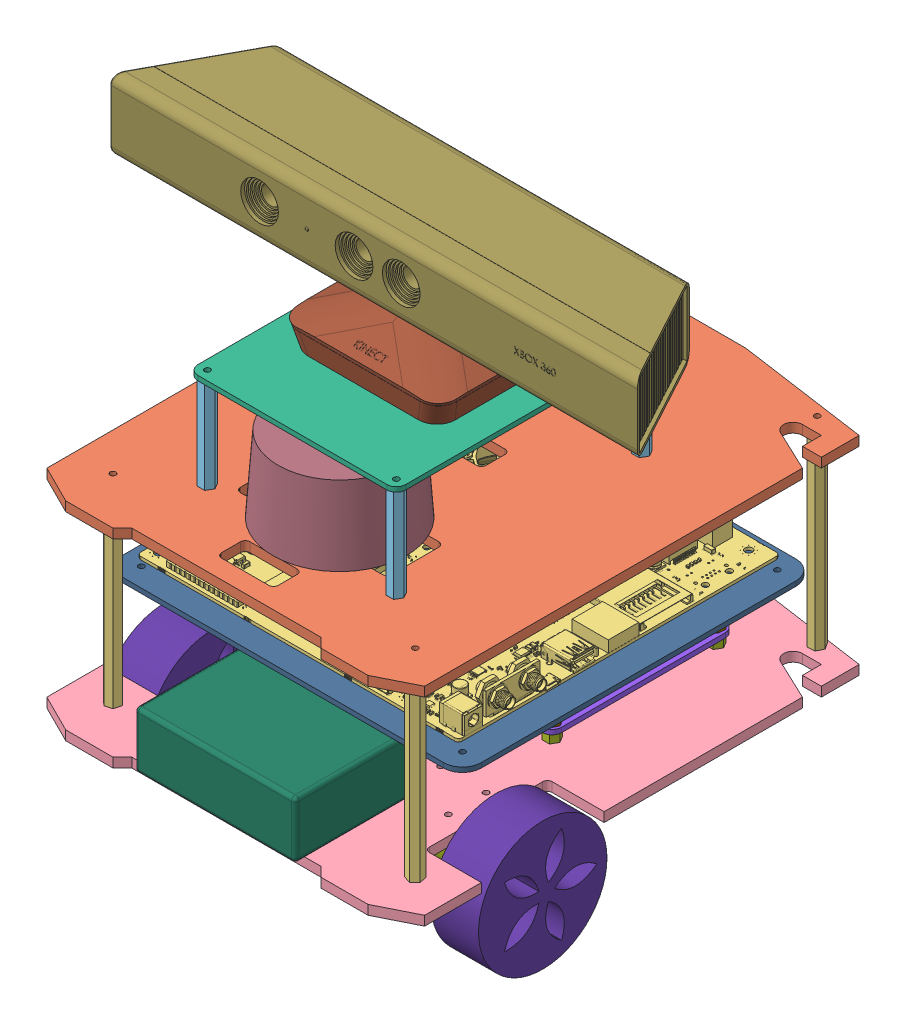
SolidWorks assembly 装配体1, configuration 默认. Lengths in mm.
Overall size (279.32 286 251).
37 component instances, 21 part files, 74 mates.
Components (placement in the parent):
- 电机支架-1: 电机支架 [默认] at (-13.0995 14.6371 109.2273) x (0 0 1) z (1 0 0) size (30 32 40)
- 上顶板-1: 上顶板 [默认] at (-83.0995 119.6371 56.7273) size (200 5 250)
- 铜柱-1: 铜柱 [默认] at (-163.0995 19.6371 156.7273) x (0.246222 0 -0.969214) z (0.969214 0 0.246222) size (8 100 6.94)
- 下地板-1: 下地板 [默认] at (-83.0995 14.6371 56.7273) size (200 5 250)
- 铜柱-2: 铜柱 [默认] at (-3.0995 19.6371 156.7273) x (0.949758 0 0.312985) z (-0.312985 0 0.949758) size (8 100 6.94)
- 铜柱-3: 铜柱 [默认] at (-163.0995 19.6371 -56.0791) size (8 100 6.94)
- 铜柱-4: 铜柱 [默认] at (-3.0995 19.6371 -56.0791) x (0.446339 0 -0.894864) z (0.894864 0 0.446339) size (8 100 6.94)
- 电机支架-2: 电机支架 [默认] at (-153.0995 14.6371 109.2273) x (0 0 -1) z (-1 0 0) size (30 32 40)
- 短铜柱-1: 短铜柱 [默认] at (-33.0995 124.6371 136.7273) size (8 50 6.94)
- 短铜柱-2: 短铜柱 [默认] at (-133.0995 124.6371 6.7273) size (8 50 6.94)
- 短铜柱-3: 短铜柱 [默认] at (-133.0995 124.6371 136.7273) size (8 50 6.94)
- 短铜柱-4: 短铜柱 [默认] at (-33.0995 124.6371 6.7273) size (8 50 6.94)
- 摄像头底板-1: 摄像头底板 [默认] at (0 -2.5 0) size (110 2.5 140)
- 超短铜柱-1: 超短铜柱 [默认] at (-30.5685 19.6371 56.7273) size (8 5.19 6.94)
- 超短铜柱-2: 超短铜柱 [默认] at (-30.5685 19.6371 -29.9177) size (8 5.19 6.94)
- 超短铜柱-3: 超短铜柱 [默认] at (-135.6304 19.6371 -29.9177) size (8 5.19 6.94)
- 超短铜柱-4: 超短铜柱 [默认] at (-135.6304 19.6371 56.7273) size (8 5.19 6.94)
- 下位机底板-1: 下位机底板 [默认] at origin size (115.06 2.5 96.65)
- tx2短铜柱-1: tx2短铜柱 [默认] at (-135.6304 27.1371 56.7273) x (0.774134 0 -0.633021) z (0.633021 0 0.774134) size (8 40 6.94)
- tx2短铜柱-2: tx2短铜柱 [默认] at (-30.5685 27.1371 56.7273) x (0.996933 0 -0.078265) z (0.078265 0 0.996933) size (8 40 6.94)
- tx2短铜柱-3: tx2短铜柱 [默认] at (-30.5685 27.1371 -29.9177) x (0.794955 0 0.606669) z (-0.606669 0 0.794955) size (8 40 6.94)
- tx2短铜柱-4: tx2短铜柱 [默认] at (-135.6304 27.1371 -29.9177) x (0.936829 0 0.349787) z (-0.349787 0 0.936829) size (8 40 6.94)
- tx2底板-1: tx2底板 [默认] at origin size (190 2.5 186.65)
- final kinect-1: final kinect [Default] at (-85.2291 193.8126 70.7637) size (279.32 72.5 71.02)
  - lower part-1: lower part [Default] at (2.1296 -16.1755 0.9636) size (86.05 27.21 71.02)
  - kinect upper part-1: kinect upper part [Default] at (2.268 17.8245 -1.5083) size (279.32 60 60)
- 雷达-1: 雷达 [默认] at (-83.0995 124.6371 116.7273) size (70.59 40 70.59)
- arduino MEGA2650-1: arduino MEGA2650 [默认] at (-37.5334 28.7371 -34.9177) x (0 0 -1) z (1 0 0) size (53.35 15.26 107.97)
- 电池-1: 电池 [默认] at (-83.0995 19.6371 152.7273) x (0 0 -1) z (1 0 0) size (60 30 85)
- 电机-1: 电机 [默认] at (-65.0995 -2.3629 109.2273) x (0 -1 0) z (0 0 1) size (25 70 25)
- 电机-2: 电机 [默认] at (-101.0995 -2.3629 109.2273) x (0 -1 0) z (0 0 -1) size (25 70 25)
- 轮子-1: 轮子 [默认] at (-183.0995 -2.3629 109.2273) x (0 -1 0) z (0 0 1) size (68 25 68)
- 轮子-2: 轮子 [默认] at (-8.0995 -2.3629 109.2273) x (0 -1 0) z (0 0 1) size (68 25 68)
- 板-1: 板 [默认] at (-83.0995 13.6371 -43.2727) size (40 1 40)
- 架-1: 架 [默认] at (-83.0995 13.6371 -43.2727) x (-1 0 0) z (0 0 1) size (16 36 30)
- 轮-1: 轮 [默认] at (-78.0995 -17.3629 -44.1872) x (0 1 0) z (0 0 1) size (35 10 35)
- tx2整体-1: tx2整体 [Default] at (-120.4205 78.1971 41.0823) x (1 0 0) z (0 1 0) size (186.12 170.18 41.03)
Mates (geometry in assembly coordinates):
- 同心1: concentric: cylinder of 铜柱-1 through (-163.0995 29.6371 156.7273) axis (0 -1 0) radius 1.5; cylinder of 下地板-1 through (-163.0995 9.6371 156.7273) axis (0 1 0) radius 1.5
- 重合1: coincident: plane of 铜柱-1 through (-163.0995 19.6371 156.7273) normal (0 -1 0); plane of 下地板-1 through (-83.0995 19.6371 56.7273) normal (0 1 0)
- 同心2: concentric: cylinder of 下地板-1 through (-3.0995 9.6371 156.7273) axis (0 1 0) radius 1.5; cylinder of 铜柱-2 through (-3.0995 29.6371 156.7273) axis (0 -1 0) radius 1.5
- 重合2: coincident: plane of 下地板-1 through (-83.0995 19.6371 56.7273) normal (0 1 0); plane of 铜柱-2 through (-3.0995 19.6371 156.7273) normal (0 -1 0)
- 重合3: coincident: plane of 下地板-1 through (-83.0995 19.6371 56.7273) normal (0 1 0); plane of 铜柱-3 through (-163.0995 19.6371 -56.0791) normal (0 -1 0)
- 同心3: concentric: cylinder of 下地板-1 through (-163.0995 9.6371 -56.0791) axis (0 1 0) radius 1.5; cylinder of 铜柱-3 through (-163.0995 29.6371 -56.0791) axis (0 -1 0) radius 1.5
- 同心4: concentric: cylinder of 下地板-1 through (-3.0995 9.6371 -56.0791) axis (0 1 0) radius 1.5; cylinder of 铜柱-4 through (-3.0995 29.6371 -56.0791) axis (0 -1 0) radius 1.5
- 重合4: coincident: plane of 下地板-1 through (-83.0995 19.6371 56.7273) normal (0 1 0); plane of 铜柱-4 through (-3.0995 19.6371 -56.0791) normal (0 -1 0)
- 重合5: coincident: plane of 上顶板-1 through (-83.0995 119.6371 56.7273) normal (0 -1 0); plane of 铜柱-1 through (-163.0995 119.6371 156.7273) normal (0 1 0)
- 同心5: concentric: cylinder of 上顶板-1 through (-163.0995 114.6371 156.7273) axis (0 1 0) radius 1.5; cylinder of 铜柱-1 through (-163.0995 109.6371 156.7273) axis (0 1 0) radius 1.5
- 同心6: concentric: cylinder of 上顶板-1 through (-3.0995 114.6371 156.7273) axis (0 1 0) radius 1.5; cylinder of 铜柱-2 through (-3.0995 109.6371 156.7273) axis (0 1 0) radius 1.5
- 重合6: coincident: plane of 电机支架-1 through (-50.5995 14.6371 96.7273) normal (0 1 0); plane of 下地板-1 through (-83.0995 14.6371 56.7273) normal (0 -1 0)
- 重合7: coincident: plane of 电机支架-1 through (-13.0995 12.6371 94.2273) normal (1 0 0); plane of 下地板-1 through (-13.0995 9.6371 139.2273) normal (1 0 0)
- 重合8: coincident: plane of 电机支架-1 through (-13.0995 14.6371 109.2273) normal (0 0 1); plane of 下地板-1 through (-83.0995 14.6371 109.2273) normal (0 0 1)
- 重合9: coincident: plane of 下地板-1 through (-83.0995 14.6371 56.7273) normal (0 -1 0); plane of 电机支架-2 through (-115.5995 14.6371 121.7273) normal (0 1 0)
- 同心7: concentric: cylinder of 下地板-1 through (-119.0995 24.6371 99.2273) axis (0 -1 0) radius 1.5; cylinder of 电机支架-2 through (-119.0995 2.6371 99.2273) axis (0 1 0) radius 1.5
- 同心8: concentric: cylinder of 下地板-1 through (-119.0995 24.6371 119.2273) axis (0 -1 0) radius 1.5; cylinder of 电机支架-2 through (-119.0995 2.6371 119.2273) axis (0 1 0) radius 1.5
- 同心9: concentric: cylinder of 上顶板-1 through (-133.0995 114.6371 136.7273) axis (0 1 0) radius 1.5; cylinder of 短铜柱-3 through (-133.0995 134.6371 136.7273) axis (0 -1 0) radius 1.5
- 同心10: concentric: cylinder of 上顶板-1 through (-33.0995 114.6371 136.7273) axis (0 1 0) radius 1.5; cylinder of 短铜柱-1 through (-33.0995 134.6371 136.7273) axis (0 -1 0) radius 1.5
- 同心11: concentric: cylinder of 上顶板-1 through (-133.0995 114.6371 6.7273) axis (0 1 0) radius 1.5; cylinder of 短铜柱-2 through (-133.0995 134.6371 6.7273) axis (0 -1 0) radius 1.5
- 同心12: concentric: cylinder of 上顶板-1 through (-33.0995 114.6371 6.7273) axis (0 1 0) radius 1.5; cylinder of 短铜柱-4 through (-33.0995 134.6371 6.7273) axis (0 -1 0) radius 1.5
- 重合10: coincident: plane of 上顶板-1 through (-83.0995 124.6371 56.7273) normal (0 1 0); plane of 短铜柱-4 through (-33.0995 124.6371 6.7273) normal (0 -1 0)
- 重合11: coincident: plane of 上顶板-1 through (-83.0995 124.6371 56.7273) normal (0 1 0); plane of 短铜柱-2 through (-133.0995 124.6371 6.7273) normal (0 -1 0)
- 重合12: coincident: plane of 上顶板-1 through (-83.0995 124.6371 56.7273) normal (0 1 0); plane of 短铜柱-3 through (-133.0995 124.6371 136.7273) normal (0 -1 0)
- 重合13: coincident: plane of 上顶板-1 through (-83.0995 124.6371 56.7273) normal (0 1 0); plane of 短铜柱-1 through (-33.0995 124.6371 136.7273) normal (0 -1 0)
- 同心13: concentric: cylinder of 下地板-1 through (-30.5685 9.6371 56.7273) axis (0 1 0) radius 1.5; cylinder of 超短铜柱-1 through (-30.5685 29.6371 56.7273) axis (0 -1 0) radius 1.5
- 同心14: concentric: cylinder of 下地板-1 through (-30.5685 9.6371 -29.9177) axis (0 1 0) radius 1.5; cylinder of 超短铜柱-2 through (-30.5685 29.6371 -29.9177) axis (0 -1 0) radius 1.5
- 同心15: concentric: cylinder of 下地板-1 through (-135.6304 9.6371 -29.9177) axis (0 1 0) radius 1.5; cylinder of 超短铜柱-3 through (-135.6304 29.6371 -29.9177) axis (0 -1 0) radius 1.5
- 同心16: concentric: cylinder of 下地板-1 through (-135.6304 9.6371 56.7273) axis (0 1 0) radius 1.5; cylinder of 超短铜柱-4 through (-135.6304 29.6371 56.7273) axis (0 -1 0) radius 1.5
- 重合14: coincident: plane of 下地板-1 through (-83.0995 19.6371 56.7273) normal (0 1 0); plane of 超短铜柱-1 through (-30.5685 19.6371 56.7273) normal (0 -1 0)
- 重合15: coincident: plane of 下地板-1 through (-83.0995 19.6371 56.7273) normal (0 1 0); plane of 超短铜柱-2 through (-30.5685 19.6371 -29.9177) normal (0 -1 0)
- 重合16: coincident: plane of 下地板-1 through (-83.0995 19.6371 56.7273) normal (0 1 0); plane of 超短铜柱-3 through (-135.6304 19.6371 -29.9177) normal (0 -1 0)
- 重合17: coincident: plane of 下地板-1 through (-83.0995 19.6371 56.7273) normal (0 1 0); plane of 超短铜柱-4 through (-135.6304 19.6371 56.7273) normal (0 -1 0)
- 同心18: concentric: cylinder of 下位机底板-1 through (-135.6304 27.1371 56.7273) axis (0 -1 0) radius 1.5; cylinder of tx2短铜柱-1 through (-135.6304 37.1371 56.7273) axis (0 -1 0) radius 1.5
- 同心19: concentric: cylinder of 下位机底板-1 through (-30.5685 27.1371 56.7273) axis (0 -1 0) radius 1.5; cylinder of tx2短铜柱-2 through (-30.5685 37.1371 56.7273) axis (0 -1 0) radius 1.5
- 同心20: concentric: cylinder of 下位机底板-1 through (-135.6304 27.1371 -29.9177) axis (0 -1 0) radius 1.5; cylinder of tx2短铜柱-4 through (-135.6304 37.1371 -29.9177) axis (0 -1 0) radius 1.5
- 同心21: concentric: cylinder of 下位机底板-1 through (-30.5685 27.1371 -29.9177) axis (0 -1 0) radius 1.5; cylinder of tx2短铜柱-3 through (-30.5685 37.1371 -29.9177) axis (0 -1 0) radius 1.5
- 重合19: coincident: plane of 下位机底板-1 through (-135.6304 27.1371 -29.9177) normal (0 1 0); plane of tx2短铜柱-3 through (-30.5685 27.1371 -29.9177) normal (0 -1 0)
- 重合20: coincident: plane of 下位机底板-1 through (-135.6304 27.1371 -29.9177) normal (0 1 0); plane of tx2短铜柱-4 through (-135.6304 27.1371 -29.9177) normal (0 -1 0)
- 重合21: coincident: plane of 下位机底板-1 through (-135.6304 27.1371 -29.9177) normal (0 1 0); plane of tx2短铜柱-1 through (-135.6304 27.1371 56.7273) normal (0 -1 0)
- 重合22: coincident: plane of 下位机底板-1 through (-135.6304 27.1371 -29.9177) normal (0 1 0); plane of tx2短铜柱-2 through (-30.5685 27.1371 56.7273) normal (0 -1 0)
- 重合23: coincident: plane of 摄像头底板-1 through (-133.0995 177.1371 136.7273) normal (0 1 0); plane of final kinect-1/lower part-1 through (-111.7434 177.1371 94.0441) normal (0 -1 0)
- 重合24: coincident: plane of 短铜柱-1 through (-33.0995 174.6371 136.7273) normal (0 1 0); plane of 摄像头底板-1 through (-133.0995 174.6371 136.7273) normal (0 -1 0)
- 重合25: coincident: plane of 摄像头底板-1 through (-83.0995 -2.5 0) normal (1 0 0); plane of final kinect-1/lower part-1 through (-83.0995 177.6371 71.7273) normal (1 0 0)
- 重合26: coincident: plane of 摄像头底板-1 through (0 -2.5 71.7273) normal (0 0 -1); plane of final kinect-1/lower part-1 through (-83.0995 177.6371 71.7273) normal (0 0 1)
- 同心22: concentric: cylinder of 短铜柱-3 through (-133.0995 164.6371 136.7273) axis (0 1 0) radius 1.5; cylinder of 摄像头底板-1 through (-133.0995 177.1371 136.7273) axis (0 -1 0) radius 1.5
- 重合28: coincident: plane of 上顶板-1 through (-83.0995 119.6371 56.7273) normal (1 0 0); plane of 雷达-1 through (-83.0995 124.6371 116.7273) normal (1 0 0)
- 重合29: coincident: plane of 上顶板-1 through (-83.0995 119.6371 116.7273) normal (0 0 1); plane of 雷达-1 through (-83.0995 124.6371 116.7273) normal (0 0 1)
- 重合30: coincident: plane of 上顶板-1 through (-83.0995 124.6371 56.7273) normal (0 1 0); plane of 雷达-1 through (-83.0995 124.6371 116.7273) normal (0 -1 0)
- 相切1: tangent: plane of 下位机底板-1 through (-135.6304 27.1371 -29.9177) normal (0 1 0); face of arduino MEGA2650-1
- 相切2: tangent: plane of 下位机底板-1 through (-135.6304 27.1371 -34.9177) normal (0 0 -1); face of arduino MEGA2650-1
- 重合31: coincident: plane of 下地板-1 through (-83.0995 19.6371 56.7273) normal (0 1 0); plane of 电池-1 through (-42.5995 19.6371 180.7273) normal (0 -1 0)
- 重合32: coincident: plane of 下地板-1 through (-83.0995 14.6371 56.7273) normal (1 0 0); plane of 电池-1 through (-83.0995 19.6371 152.7273) normal (1 0 0)
- 距离3: distance = 6 mm: plane of 电池-1 through (-123.5995 49.6371 182.7273) normal (0 0 1); plane of 下地板-1 through (-133.0995 -15.3629 176.7273) normal (0 0 1)
- 重合33: coincident: plane of 电机支架-1 through (-15.0995 14.6371 109.2273) normal (-1 0 0); plane of 电机-1 through (-15.0995 -2.3629 109.2273) normal (1 0 0)
- 同心23: concentric: cylinder of 电机支架-1 through (-15.0995 -2.3629 109.2273) axis (1 0 0) radius 5; circle of 电机-1
- 重合35: coincident: plane of 电机支架-2 through (-151.0995 14.6371 109.2273) normal (1 0 0); plane of 电机-2 through (-151.0995 -2.3629 109.2273) normal (-1 0 0)
- 同心24: concentric: cylinder of 电机支架-2 through (-143.0995 -2.3629 99.2273) axis (-1 0 0) radius 1.5; cylinder of 电机-2 through (-141.0995 -2.3629 99.2273) axis (-1 0 0) radius 1.5
- 同心25: concentric: cylinder of 电机支架-2 through (-143.0995 -2.3629 119.2273) axis (-1 0 0) radius 1.5; cylinder of 电机-2 through (-141.0995 -2.3629 119.2273) axis (-1 0 0) radius 1.5124
- 同心26: concentric: cylinder of 电机-2 through (-171.0995 -2.3629 109.2273) axis (1 0 0) radius 2.5; cylinder of 轮子-1 through (-158.0995 -2.3629 109.2273) axis (-1 0 0) radius 34
- 重合36: coincident: plane of 下地板-1 through (-183.0995 19.6371 -68.2727) normal (-1 0 0); plane of 轮子-1 through (-183.0995 -2.3629 109.2273) normal (-1 0 0)
- 同心27: concentric: cylinder of 电机-1 through (4.9005 -2.3629 109.2273) axis (-1 0 0) radius 2.5; cylinder of 轮子-2 through (16.9005 -2.3629 109.2273) axis (-1 0 0) radius 34
- 重合37: coincident: plane of 下地板-1 through (16.9005 19.6371 -68.2727) normal (1 0 0); plane of 轮子-2 through (16.9005 -2.3629 109.2273) normal (1 0 0)
- 重合38: coincident: plane of 下地板-1 through (-83.0995 14.6371 56.7273) normal (0 -1 0); plane of 板-1 through (-98.0995 14.6371 -28.2727) normal (0 1 0)
- 重合39: coincident: plane of 下地板-1 through (-83.0995 14.6371 56.7273) normal (1 0 0); plane of 板-1 through (-83.0995 13.6371 -43.2727) normal (1 0 0)
- 距离5: distance = 5 mm: plane of 板-1 through (-98.0995 14.6371 -63.2727) normal (0 0 -1); plane of 下地板-1 through (-183.0995 19.6371 -68.2727) normal (0 0 -1)
- 重合41: coincident: plane of 板-1 through (-98.0995 13.6371 -28.2727) normal (0 -1 0); plane of 架-1 through (-76.0995 13.6371 -29.2727) normal (0 1 0)
- 重合42: coincident: plane of 下地板-1 through (-83.0995 14.6371 56.7273) normal (1 0 0); plane of 架-1 through (-83.0995 13.6371 -43.2727) normal (-1 0 0)
- 重合43: coincident: plane of 板-1 through (-83.0995 13.6371 -43.2727) normal (0 0 1); plane of 架-1 through (-83.0995 13.6371 -43.2727) normal (0 0 1)
- 同心28: concentric: cylinder of 架-1 through (-90.0995 -17.3629 -44.1872) axis (-1 0 0) radius 5; cylinder of 轮-1 through (-88.0995 -17.3629 -44.1872) axis (1 0 0) radius 17.5
- 重合45: coincident: plane of 架-1 through (-83.0995 13.6371 -43.2727) normal (-1 0 0); plane of 轮-1 through (-83.0995 -17.3629 -44.1872) normal (-1 0 0)
- 重合46: coincident: plane of tx2底板-1 through (-168.0995 69.6371 -29.9177) normal (0 1 0); plane of tx2整体-1 through (-168.0995 69.6371 -29.9177) normal (0 -1 0)
- 同心29: concentric: cylinder of tx2底板-1 through (-168.0995 69.6371 -29.9177) axis (0 -1 0) radius 1.5; cylinder of tx2整体-1 through (-168.0995 69.6371 -29.9177) axis (0 1 0) radius 1.975
- 平行1: parallel: plane of tx2底板-1 through (-178.0995 69.6371 -29.9177) normal (-1 0 0); plane of tx2整体-1 through (-173.1795 69.6371 -34.2677) normal (-1 0 0)
